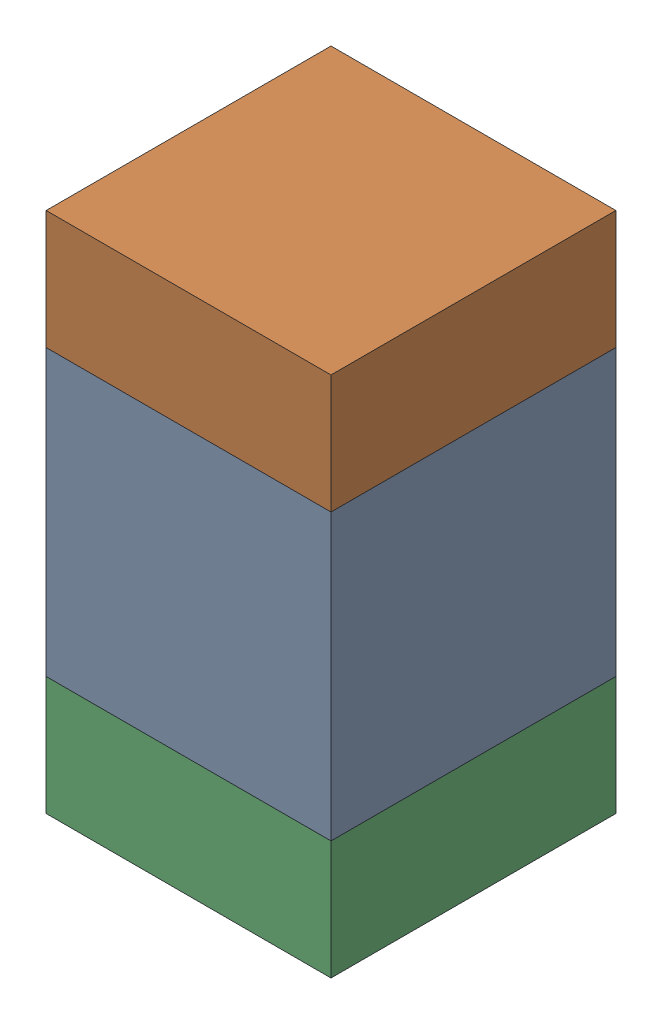
SolidWorks assembly C405PCB, configuration Default. Lengths in mm.
Overall size (0.6 1.1 0.6).
6 component instances, 2 part files, 0 mates.
Components (placement in the parent):
- 761606048-1: 761606048 [Default] at (80.8 84.9 0) size (0.6 0.6 0.6)
  - Extruded_9-1: Extruded_9 [Default] at origin size (0.6 0.6 0.6)
- 854785296-1: 854785296 [Default] at (80.8 85.325 0) size (0.6 0.25 0.6)
  - Extruded_10-1: Extruded_10 [Default] at origin size (0.6 0.25 0.6)
- 854785296-2: 854785296 [Default] at (80.8 84.475 0) size (0.6 0.25 0.6)
  - Extruded_10-1: Extruded_10 [Default] at origin size (0.6 0.25 0.6)
